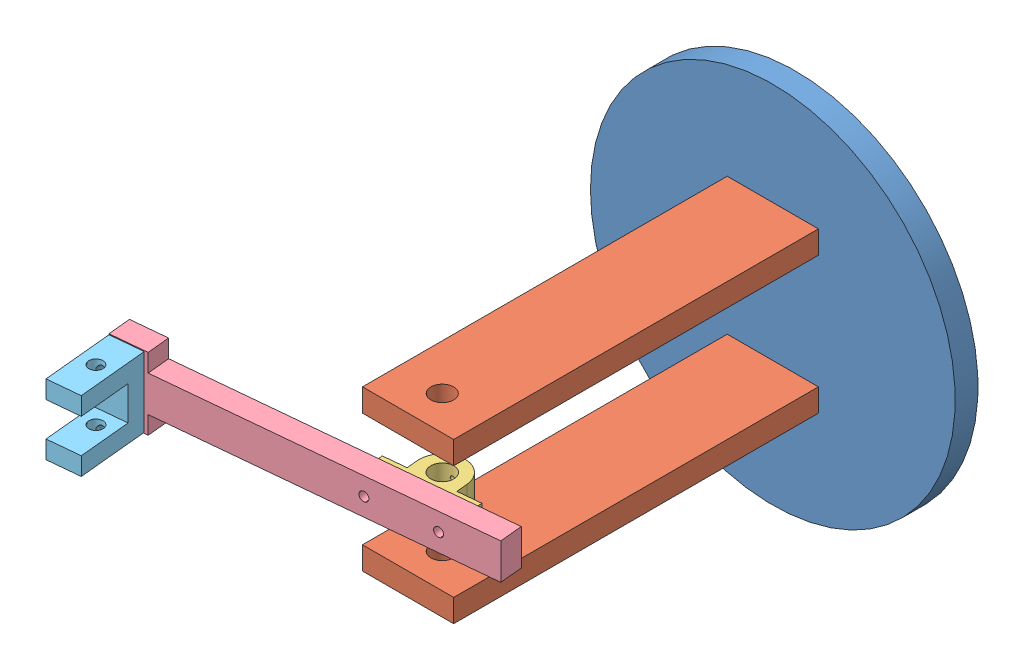
SolidWorks assembly arm assembly, configuration Default. Lengths in mm.
Overall size (248.89 203.2 275.27).
6 component instances, 5 part files, 12 mates.
Components (placement in the parent):
- base-1: base [Default] at origin size (203.2 203.2 12.7)
- column-1: column [Default] at (0 44.45 12.7) x (1 0 0) z (0 -1 0) size (50.8 203.2 12.7)
- column-2: column [Default] at (0 -31.75 12.7) x (1 0 0) z (0 -1 0) size (50.8 203.2 12.7)
- mounting bracket-1: mounting bracket [Default] at (1.2189 -6.35 209.4914) x (0.995383 0 -0.095978) z (0 1 0) size (50.8 25.4 12.7)
- linear actuator mount-1: linear actuator mount [Default] at (-147.2923 0 223.8114) x (0 -1 0) z (0.095978 0 0.995383) size (40 200 12.7)
- U bracket-1: U bracket [Default] at (-146.0734 0 236.4527) x (0 1 0) z (0.995383 0 -0.095978) size (39 39 18)
Mates (geometry in assembly coordinates):
- Coincident1: coordinate: point of base-1; point of assembly
- Coincident2: coincident anti-aligned: plane of base-1 through (0 0 12.7) normal (0 0 1); plane of column-1 through (-25.4 31.75 12.7) normal (0 0 -1)
- Coincident3: coincident aligned: plane of column-1 through (0 44.45 12.7) normal (1 0 0); plane of assembly through (0 0 0) normal (1 0 0)
- Distance1: distance = 63.5 mm anti-aligned: plane of column-1 through (0 31.75 12.7) normal (0 -1 0); plane of column-2 through (0 -31.75 12.7) normal (0 1 0)
- Concentric1: concentric anti-aligned: cylinder of column-1 through (0 31.75 196.85) axis (0 1 0) radius 6.35; cylinder of mounting bracket-1 through (0 6.35 196.85) axis (0 -1 0) radius 6.4135
- Width1: width anti-aligned: plane of column-2 through (0 -31.75 12.7) normal (0 1 0); plane of column-1 through (0 31.75 12.7) normal (0 -1 0); plane of mounting bracket-1 through (0 -6.35 196.85) normal (0 -1 0); plane of mounting bracket-1 through (0 6.35 196.85) normal (0 1 0)
- Coincident5: coincident anti-aligned: plane of mounting bracket-1 through (26.5017 6.35 207.0535) normal (0.095978 0 0.995383); plane of linear actuator mount-1 through (-147.2923 0 223.8114) normal (-0.095978 0 -0.995383)
- Width2: width anti-aligned: plane of linear actuator mount-1 through (-126.1657 -10 234.5332) normal (0 -1 0); plane of linear actuator mount-1 through (53.0033 10 217.257) normal (0 1 0); plane of mounting bracket-1 through (0 6.35 196.85) normal (0 1 0); plane of mounting bracket-1 through (0 -6.35 196.85) normal (0 -1 0)
- Distance2: distance = 25.4 mm aligned: plane of mounting bracket-1 through (25.8922 6.35 200.7328) normal (0.995383 0 -0.095978); plane of linear actuator mount-1 through (53.0033 -10 217.257) normal (0.995383 0 -0.095978)
- Coincident8: coincident anti-aligned: plane of linear actuator mount-1 through (-146.0734 0 236.4527) normal (0.095978 0 0.995383); plane of U bracket-1 through (-128.1565 -19.5 234.7251) normal (-0.095978 0 -0.995383)
- Coincident9: coincident aligned: plane of linear actuator mount-1 through (-146.0734 20 236.4527) normal (-0.995383 0 0.095978); plane of U bracket-1 through (-146.0734 0 236.4527) normal (-0.995383 0 0.095978)
- Coincident10: coincident aligned: plane of U bracket-1 through (-146.0734 0 236.4527) normal (0 1 0); plane of assembly through (0 0 0) normal (0 1 0)
